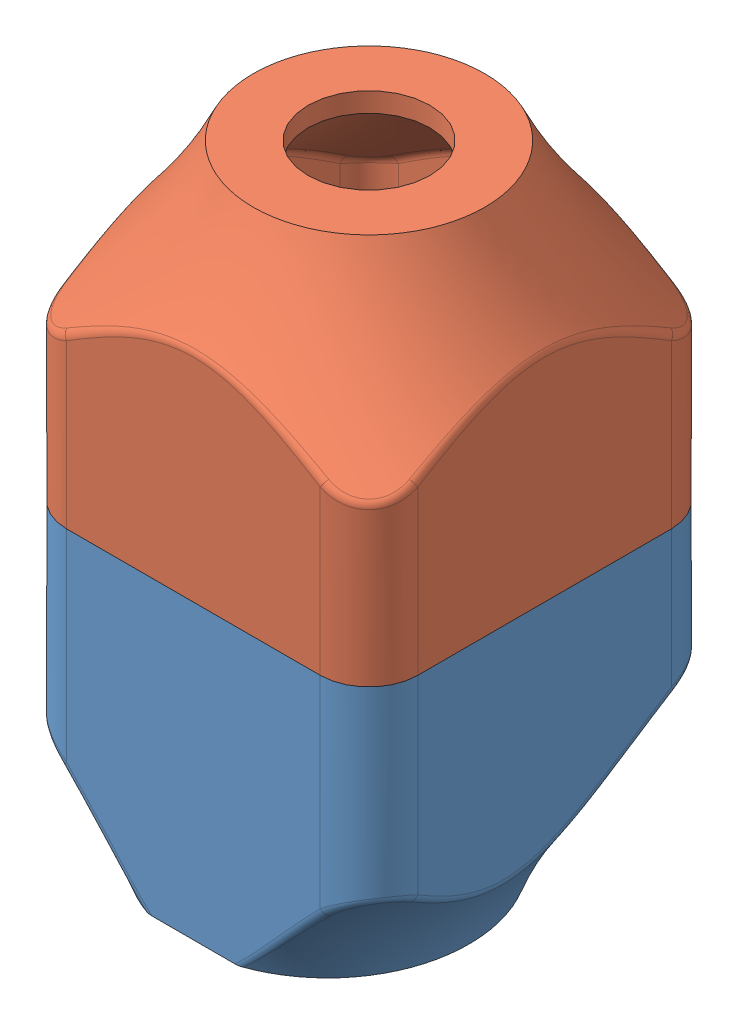
SolidWorks assembly 装配体2, configuration 默认. Lengths in mm.
Overall size (38.98 62.03 37.75).
2 component instances, 2 part files, 2 mates.
Components (placement in the parent):
- E0111A-2: E0111A [默认] at (67.0604 -7.9694 -34.1258) size (38.98 30.03 36.63)
- E0111B-2: E0111B [默认] at (67.0604 54.0306 -34.1258) x (1 0 0) z (0 0 -1) size (37.63 37 37.75)
Mates (geometry in assembly coordinates):
- 重合3: coincident anti-aligned: line of E0111A-2 through (80.0604 22.0306 -52.1258) axis (-1 0 0); line of E0111B-2 through (54.0604 22.0306 -52.1258) axis (1 0 0)
- 重合4: coincident anti-aligned: line of E0111A-2 through (49.0604 22.0306 -47.1258) axis (0 0 1); line of E0111B-2 through (49.0604 22.0306 -21.1258) axis (0 0 -1)
